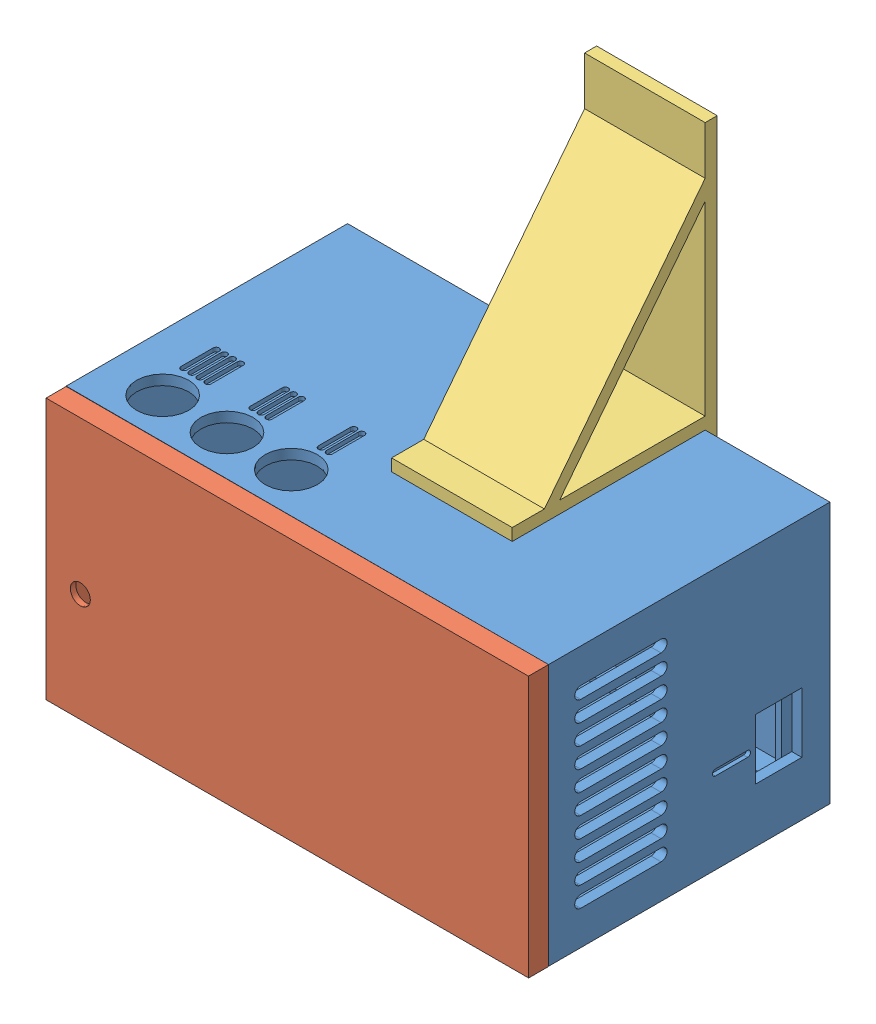
SolidWorks assembly box_support_assembly, configuration Default. Lengths in mm.
Overall size (120.05 136.23 78).
3 component instances, 3 part files, 5 mates.
Components (placement in the parent):
- box-1: box [Default] at origin size (120 65 70)
- cover-1: cover [Default] at (0 64.9144 72.5) x (1 0.000713 0) z (0 0 -1) size (120 65 7.5)
- support-1: support [Default] at (48.9594 66.5 10) x (0 -1 0) z (0 0 1) size (136.23 30 51)
Mates (geometry in assembly coordinates):
- Coincident7: coincident anti-aligned: plane of box-1 through (0 0 70) normal (0 0 1); plane of cover-1 through (0 64.9144 70) normal (0 0 -1)
- Coincident8: coincident: point of box-1; point of cover-1
- Coincident9: coincident: plane of box-1 through (0 65 0) normal (0 1 0); plane of support-1 through (88.9594 65 48) normal (0 -1 0)
- Coincident10: coincident: plane of box-1 through (0 0 0) normal (0 0 -1); plane of support-1 through (88.9594 65 0) normal (0 0 1)
- Lock1: lock: unknown of box-1; unknown of support-1
